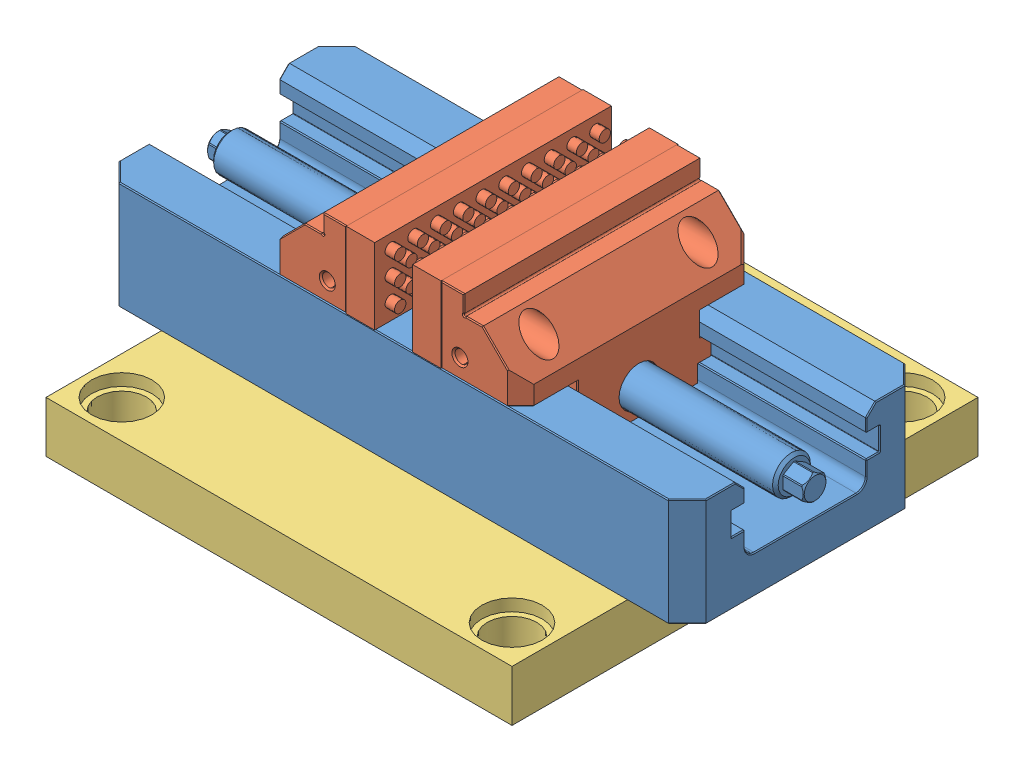
SolidWorks assembly ETAU VARIO 125, configuration Défaut. Lengths in mm.
Overall size (315 124 246).
5 component instances, 3 part files, 3 mates.
Components (placement in the parent):
- Copie de 42202^ETAU VARIO 125-1: Copie de 42202^ETAU VARIO 125 [Défaut] at (9.1729 3.3972 315) size (315 97 125) (virtual)
  - Copie de 47305^Copie de 42202_ETAU VARIO 125-1: Copie de 47305^Copie de 42202_ETAU VARIO 125 [Défaut] at origin size (315 57 125) (virtual)
  - Copie de 42125^Copie de 42202_ETAU VARIO 125-1: Copie de 42125^Copie de 42202_ETAU VARIO 125 [Défaut] at (25 38.6 0) x (0 0 -1) z (1 0 0) size (125 73 62) (virtual)
  - Copie de 42125^Copie de 42202_ETAU VARIO 125-2: Copie de 42125^Copie de 42202_ETAU VARIO 125 [Défaut] at (-25 38.6 0) x (0 0 1) z (-1 0 0) size (125 73 62) (virtual)
- Copie de PALETTE 246 246^ETAU VARIO 125-1: Copie de PALETTE 246 246^ETAU VARIO 125 [Défaut] at (9.1729 3.3972 315) x (1 0 0) z (0 1 0) size (246 246 27) (virtual)
Mates (geometry in assembly coordinates):
- Coïncidente12: coincident: plane of Copie de 42202^ETAU VARIO 125-1/Copie de 47305^Copie de 42202_ETAU VARIO 125-1 through (-145.8271 3.3972 252.5) normal (0 -1 0); plane of Copie de PALETTE 246 246^ETAU VARIO 125-1 through (9.1729 3.3972 315) normal (0 1 0)
- Coïncidente13: coincident: plane of Copie de 42202^ETAU VARIO 125-1/Copie de 47305^Copie de 42202_ETAU VARIO 125-1 through (9.1729 3.3972 315) normal (-1 0 0); plane of Copie de PALETTE 246 246^ETAU VARIO 125-1 through (9.1729 3.3972 315) normal (1 0 0)
- Coïncidente14: coincident: plane of Copie de 42202^ETAU VARIO 125-1/Copie de 47305^Copie de 42202_ETAU VARIO 125-1 through (9.1729 3.3972 315) normal (0 0 -1); plane of Copie de PALETTE 246 246^ETAU VARIO 125-1 through (9.1729 3.3972 315) normal (0 0 -1)
